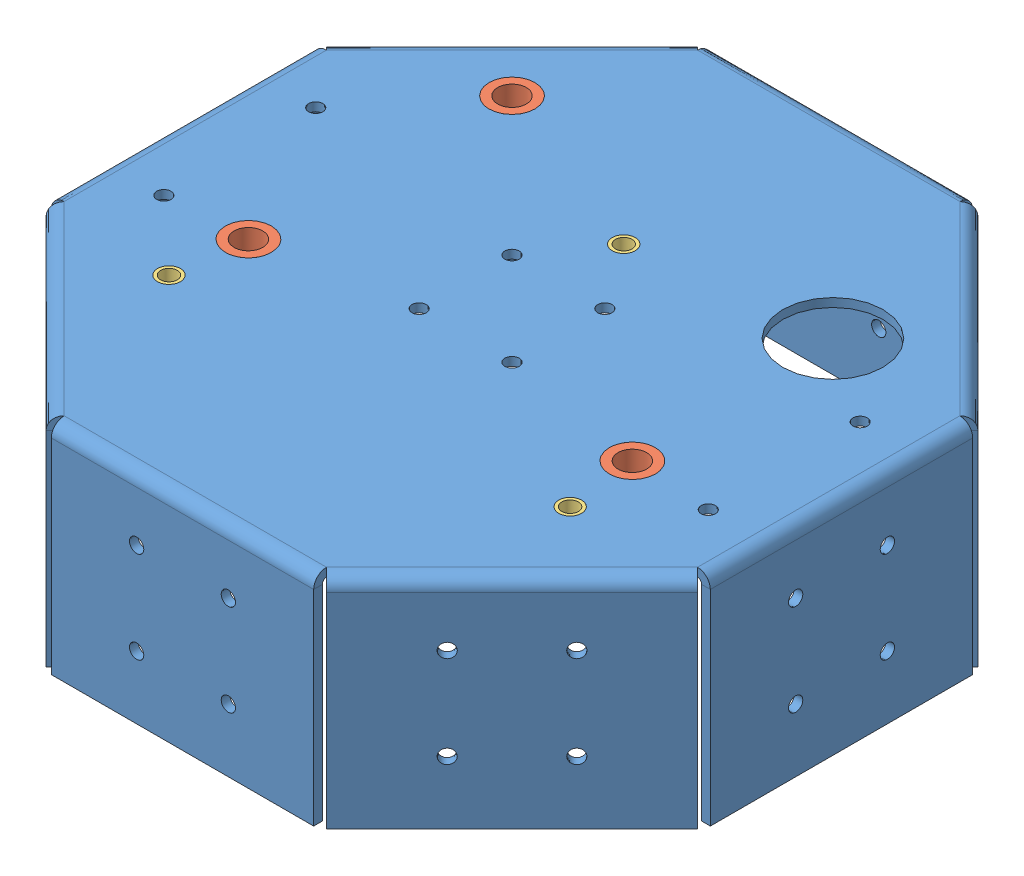
SolidWorks assembly Embase, configuration Défaut. Lengths in mm.
Overall size (114.99 38 114.99).
7 component instances, 3 part files, 12 mates.
Components (placement in the parent):
- tole_embase_pliee-1: tole_embase_pliee [Défaut] at (-8.2808 3.3418 0) size (114.99 38 114.99)
- insert-d9-1: insert-d9 [Défaut] at (-41.7774 1.8418 12.4966) size (9 11 9)
- insert-d9-2: insert-d9 [Défaut] at (25.2158 1.8418 12.4966) size (9 11 9)
- insert-d9-3: insert-d9 [Défaut] at (-40.4517 1.8418 -32.171) size (9 11 9)
- insert-d5-1: insert-d5 [Défaut] at (-43.2808 1.8418 24.8571) size (5 6 5)
- insert-d5-2: insert-d5 [Défaut] at (-8.2808 1.8418 -19.4966) size (5 6 5)
- insert-d5-3: insert-d5 [Défaut] at (26.7192 1.8418 24.8571) size (5 6 5)
Mates (geometry in assembly coordinates):
- Coïncidente1: coincident: plane of tole_embase_pliee-1 through (-8.2808 1.8418 0) normal (0 -1 0); plane of insert-d9-1 through (-41.7774 1.8418 12.4966) normal (0 1 0)
- Coaxiale1: concentric anti-aligned: cylinder of tole_embase_pliee-1 through (-41.7774 -6.6582 12.4966) axis (0 1 0) radius 4; cylinder of insert-d9-1 through (-41.7774 3.3418 12.4966) axis (0 -1 0) radius 4
- Coïncidente2: coincident: plane of tole_embase_pliee-1 through (-8.2808 1.8418 0) normal (0 -1 0); plane of insert-d9-2 through (25.2158 1.8418 12.4966) normal (0 1 0)
- Coaxiale2: concentric anti-aligned: cylinder of tole_embase_pliee-1 through (25.2158 -6.6582 12.4966) axis (0 1 0) radius 4; cylinder of insert-d9-2 through (25.2158 3.3418 12.4966) axis (0 -1 0) radius 4
- Coïncidente3: coincident: plane of tole_embase_pliee-1 through (-8.2808 1.8418 0) normal (0 -1 0); plane of insert-d9-3 through (-40.4517 1.8418 -32.171) normal (0 1 0)
- Coaxiale3: concentric anti-aligned: cylinder of tole_embase_pliee-1 through (-40.4517 -6.6582 -32.171) axis (0 1 0) radius 4; cylinder of insert-d9-3 through (-40.4517 3.3418 -32.171) axis (0 -1 0) radius 4
- Coïncidente4: coincident: plane of tole_embase_pliee-1 through (-8.2808 1.8418 0) normal (0 -1 0); plane of insert-d5-3 through (26.7192 1.8418 24.8571) normal (0 1 0)
- Coaxiale4: concentric anti-aligned: cylinder of insert-d5-3 through (26.7192 3.3418 24.8571) axis (0 -1 0) radius 2; cylinder of tole_embase_pliee-1 through (26.7192 -6.6582 24.8571) axis (0 1 0) radius 2
- Coïncidente5: coincident: plane of tole_embase_pliee-1 through (-8.2808 1.8418 0) normal (0 -1 0); plane of insert-d5-2 through (-8.2808 1.8418 -19.4966) normal (0 1 0)
- Coïncidente6: coincident: plane of tole_embase_pliee-1 through (-8.2808 1.8418 0) normal (0 -1 0); plane of insert-d5-1 through (-43.2808 1.8418 24.8571) normal (0 1 0)
- Coaxiale5: concentric anti-aligned: cylinder of tole_embase_pliee-1 through (-43.2808 -6.6582 24.8571) axis (0 1 0) radius 2; cylinder of insert-d5-1 through (-43.2808 3.3418 24.8571) axis (0 -1 0) radius 2
- Coaxiale6: concentric anti-aligned: cylinder of tole_embase_pliee-1 through (-8.2808 -6.6582 -19.4966) axis (0 1 0) radius 2; cylinder of insert-d5-2 through (-8.2808 3.3418 -19.4966) axis (0 -1 0) radius 2
